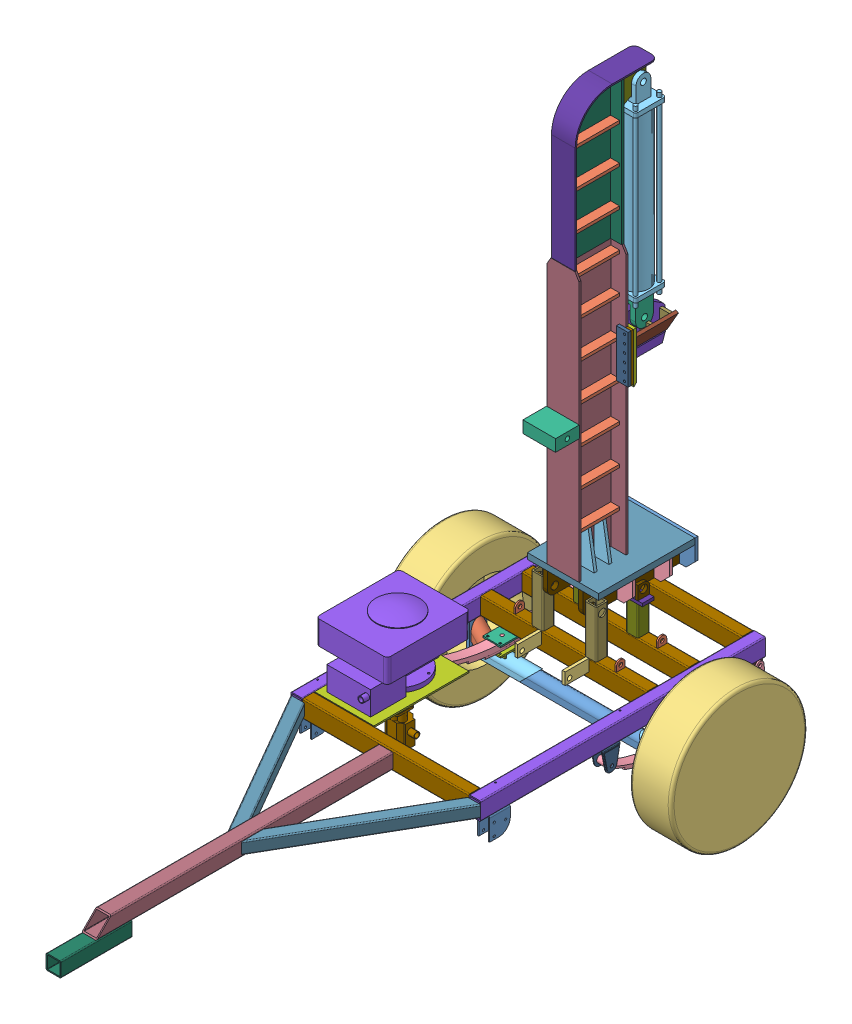
SolidWorks assembly Wood Splitter Mk4 Assb, configuration Upright. Lengths in mm.
Overall size (1041.53 2359.23 2641.6).
119 component instances, 51 part files, 48 mates.
Components (placement in the parent):
- Axle Assb-1: Axle Assb [Default] at (-785.5407 -217.0275 -452.1847) x (1 0 0) z (0 0.0044 0.99999) size (1270 586.82 669.93)
  - Axle-1: Axle [Default] at (861.7407 459.5998 794.3849) size (990.6 168.28 76.2)
  - Axle Brace-1: Axle Brace [Default] at (-125.416 485.8595 794.3849) x (0.707107 -0.707107 0) z (0 0 1) size (101.6 53.97 62.1)
  - Axle Brace-2: Axle Brace [Default] at (883.6975 485.8595 794.3849) x (-0.707107 -0.707107 0) z (0 0 -1) size (101.6 53.97 62.1)
  - Tire-1: Tire [Default] at (-166.9593 505.6373 794.3849) size (177.8 584.2 584.2)
  - Tire-2: Tire [Default] at (925.2407 505.6373 794.3849) x (-1 0 0) z (0 -0.004501 -0.99999) size (177.8 584.2 584.2)
  - 1750 Spring-1: 1750 Spring [Default] at (-1.8593 560.1132 794.3849) x (1 0 0) z (0 0 -1) size (44.45 133.46 669.92)
  - 1750 Spring-2: 1750 Spring [Default] at (760.1407 560.1132 794.3849) x (1 0 0) z (0 0 -1) size (44.45 133.46 669.92)
  - Axle Brace Horz-1: Axle Brace Horz [Default] at (158.8167 408.7998 794.3849) x (-1 0 0) z (0 0 -1) size (228.6 53.97 62.1)
  - Axle Brace Horz-2: Axle Brace Horz [Default] at (599.4648 408.7998 794.3849) size (228.6 53.97 62.1)
  - Spring Tie Plate-1: Spring Tie Plate [Default] at (-1.8593 487.2961 794.3849) size (76.2 6.35 88.9)
  - Spring Tie Plate-2: Spring Tie Plate [Default] at (760.1407 487.2961 794.3849) size (76.2 6.35 88.9)
  - Spring Seat-1: Spring Seat [Default] at (-1.8593 449.1961 794.3849) size (76.2 19.05 88.9)
  - Spring Seat-2: Spring Seat [Default] at (760.1407 449.1961 794.3849) size (76.2 19.05 88.9)
- Frame Assb-1: Frame Assb [Default] at (-1059.4886 145.9039 92.6772) size (819.15 374.65 2641.6)
  - Frame Tube Side-1: Frame Tube Side [Default] at (272.0886 310.0325 516.9228) size (50.8 76.2 1219.2)
  - Frame Tube End-1: Frame Tube End [Default] at (653.0886 310.0325 -67.2772) size (711.2 76.2 50.8)
  - Frame Tube Side-2: Frame Tube Side [Default] at (1034.0886 310.0325 516.9228) size (50.8 76.2 1219.2)
  - Spring Hanger Front-1: Spring Hanger Front [Default] at (272.0886 221.1325 567.7228) size (57.15 95.25 76.2)
  - Spring Hanger Front-2: Spring Hanger Front [Default] at (1034.0886 221.1325 567.7228) size (57.15 95.25 76.2)
  - Shackle Block-1: Shackle Block [Default] at (1034.0886 256.0575 -67.2772) size (44.45 31.75 31.75)
  - Shackle Block-2: Shackle Block [Default] at (272.0886 256.0575 -67.2772) size (44.45 31.75 31.75)
  - Frame Tube End-2: Frame Tube End [Default] at (653.0886 310.0325 1101.1228) size (711.2 76.2 50.8)
  - Frame Tube End-3: Frame Tube End [Default] at (653.0886 310.0325 339.1228) size (711.2 76.2 50.8)
  - Frame Tube End-4: Frame Tube End [Default] at (653.0886 310.0325 161.3228) size (711.2 76.2 50.8)
  - 5x8 Beam Pivot-1: 5x8 Beam Pivot [Default] at (538.7886 449.7325 339.1228) size (50.8 203.2 50.8)
  - 5x8 Beam Pivot-2: 5x8 Beam Pivot [Default] at (767.3886 449.7325 339.1228) size (50.8 203.2 50.8)
  - Frame Tounge-1: Frame Tounge [Default] at (653.0886 310.0325 1761.5228) size (63.5 63.5 1270)
  - Frame Tounge Side-1: Frame Tounge Side [Default] at (850.1665 310.0325 1438.2792) x (0.866025 0 0.5) z (-0.5 0 0.866025) size (50.8 50.8 749.3)
  - Frame Tounge Side-2: Frame Tounge Side [Default] at (456.0106 310.0325 1438.2792) x (-0.866025 0 0.5) z (0.5 0 0.866025) size (50.8 50.8 749.3)
  - Frame Tounge Extension-1: Frame Tounge Extension [Default] at (653.0886 246.5325 2396.5228) size (63.5 63.5 304.8)
  - 5x8 Beam Lock-1: 5x8 Beam Lock [Default] at (538.7886 411.6325 161.3228) size (50.8 127 50.8)
  - 5x8 Beam Lock-2: 5x8 Beam Lock [Default] at (767.3886 411.6325 161.3228) size (50.8 127 50.8)
  - 5x8 Beam Stop-1: 5x8 Beam Stop [Default] at (726.1136 481.4825 161.3228) size (171.45 12.7 50.8)
  - 5x8 Beam Lock Tab-1: 5x8 Beam Lock Tab [Default] at (519.7386 516.4075 161.3228) size (12.7 57.15 50.8)
  - 5x8 Beam Lock Tab-2: 5x8 Beam Lock Tab [Default] at (786.4386 516.4075 161.3228) size (12.7 57.15 50.8)
  - Castor Mount-1: Castor Mount [Default] at (1034.0886 221.1325 1043.9728) size (50.8 95.25 88.9)
  - Castor Mount-2: Castor Mount [Default] at (272.0886 221.1325 1043.9728) size (50.8 95.25 88.9)
  - Log Lift Clevis-1: Log Lift Clevis [Default] at (437.1886 367.1825 339.1228) size (6.35 38.1 38.1)
  - Log Lift Clevis-2: Log Lift Clevis [Default] at (437.1886 367.1825 161.3228) size (6.35 38.1 38.1)
  - Log Lift Clevis-3: Log Lift Clevis [Default] at (868.9886 367.1825 161.3228) size (6.35 38.1 38.1)
  - Log Lift Clevis-4: Log Lift Clevis [Default] at (868.9886 367.1825 339.1228) size (6.35 38.1 38.1)
  - Lift Clevis Lower-1: Lift Clevis Lower [Default] at (551.4886 322.7325 415.3228) size (12.7 50.8 101.6)
  - Lift Clevis Lower-2: Lift Clevis Lower [Default] at (754.6886 322.7325 415.3228) size (12.7 50.8 101.6)
- Shackle-1: Shackle [Default] at (0 373.5629 22.2281) x (1 0 0) z (0 -0.111002 0.99382)
- Shackle-2: Shackle [Default] at (-50.8 373.5629 22.2281) x (1 0 0) z (0 -0.111002 0.99382)
- Shackle-3: Shackle [Default] at (-762 373.5629 22.2281) x (1 0 0) z (0 -0.111002 0.99382)
- Shackle-4: Shackle [Default] at (-812.8 373.5629 22.2281) x (1 0 0) z (0 -0.111002 0.99382)
- Lion 40TH24-175-1: Lion 40TH24-175 [Retracted] at (-621.9267 1611.0795 -578.2318) size (130.18 939.8 130.18)
  - Lion 40TH24-175 Cylinder-1: Lion 40TH24-175 Cylinder [Default] at (218.7017 743.5068 730.6318) size (130.18 831.85 130.18)
  - Lion 40TH24-175 Rod-1: Lion 40TH24-175 Rod [Default] at (218.7017 721.2818 730.6318) size (101.6 822.32 101.6)
- Wedge Mk2 Assb-1: Wedge Mk2 Assb [Default] at (-365.761 1417.0554 373.2909) x (-1 0 0) z (0 0 -1) size (184.15 212.72 238.12)
  - Wedge Mk2 Base-1: Wedge Mk2 Base [Default] at (37.464 81.8685 125.6409) size (184.15 212.72 12.7)
  - Wedge Mk2-1: Wedge Mk2 [Default] at (37.464 -14.969 233.5909) size (25.4 203.2 203.2)
  - Wedge Mk2 Spacer-1: Wedge Mk2 Spacer [Default] at (-42.7048 86.631 114.5284) x (-1 0 0) z (0 0 1) size (23.81 203.2 9.53)
  - Wedge Mk2 Spacer-2: Wedge Mk2 Spacer [Default] at (117.6327 86.631 114.5284) size (23.81 203.2 9.53)
  - Wedge Mk2 Guide-1: Wedge Mk2 Guide [Default] at (104.139 86.631 103.4159) x (-1 0 0) z (0 0 1) size (50.8 203.2 12.7)
  - Wedge Mk2 Guide-2: Wedge Mk2 Guide [Default] at (-29.211 86.631 103.4159) size (50.8 203.2 12.7)
  - Wedge Mk2 Spreader-1: Wedge Mk2 Spreader [Default] at (75.564 89.1221 233.5909) x (0.866025 -0.5 0) z (0 0 1) size (12.7 101.6 203.2)
  - Wedge Mk2 Spreader-2: Wedge Mk2 Spreader [Default] at (-0.636 89.1221 233.5909) x (-0.866025 -0.5 0) z (0 0 -1) size (12.7 101.6 203.2)
  - Wedge Mk2 Spreader Support-1: Wedge Mk2 Spreader Support [Default] at (24.764 134.028 151.0409) x (-1 0 0) z (0 0 -1) size (43.99 76.2 12.7)
  - Wedge Mk2 Spreader Support-2: Wedge Mk2 Spreader Support [Default] at (24.764 134.028 233.5909) x (-1 0 0) z (0 0 -1) size (43.99 76.2 12.7)
  - Wedge Mk2 Spreader Support-3: Wedge Mk2 Spreader Support [Default] at (24.764 134.028 316.1409) x (-1 0 0) z (0 0 -1) size (43.99 76.2 12.7)
  - Wedge Mk2 Spreader Support-4: Wedge Mk2 Spreader Support [Default] at (50.164 134.028 316.1409) size (43.99 76.2 12.7)
  - Wedge Mk2 Spreader Support-5: Wedge Mk2 Spreader Support [Default] at (50.164 134.028 233.5909) size (43.99 76.2 12.7)
  - Wedge Mk2 Spreader Support-6: Wedge Mk2 Spreader Support [Default] at (50.164 134.028 151.0409) size (43.99 76.2 12.7)
- 5x8 Rail Assb-1: 5x8 Rail Assb [Default] at (-973.7037 763.2009 -461.3249) size (304.8 1885.95 527.05)
  - 5x8 Beam-1: 5x8 Beam [Default] at (570.4787 569.0354 820.0999) size (136.53 1143 209.55)
  - 5x8 Reaction Plate-1: 5x8 Reaction Plate [Default] at (570.4787 -15.1646 718.4999) size (304.8 25.4 412.75)
  - 4x8 Beam-1: 4x8 Beam [Default] at (570.4787 1445.3354 715.3249) size (101.6 609.6 201.61)
  - Clevis Mount-1: Clevis Mount [Default] at (570.4787 1696.1604 648.6499) size (25.4 152.4 133.35)
  - 4x8 Beam Bottom-1: 4x8 Beam Bottom [Default] at (570.4787 1597.7354 764.5374) size (101.6 615.95 354.01)
  - 5x8 Beam Pivot Plate-1: 5x8 Beam Pivot Plate [Default] at (494.2787 -78.6646 718.4999) size (19.05 101.6 412.75)
  - 5x8 Beam Pivot Plate-2: 5x8 Beam Pivot Plate [Default] at (646.6787 -78.6646 718.4999) size (19.05 101.6 412.75)
  - Reaction Plate Front Brace-1: Reaction Plate Front Brace [Default] at (570.4787 -65.9646 505.7749) size (304.8 127 12.7)
  - 5x8 Beam Gusset-1: 5x8 Beam Gusset [Default] at (592.7037 473.7854 820.0999) x (0 0 -1) z (1 0 0) size (193.68 12.7 38.1)
  - 5x8 Beam Gusset-2: 5x8 Beam Gusset [Default] at (592.7037 315.0354 820.0999) x (0 0 -1) z (1 0 0) size (193.68 12.7 38.1)
  - 5x8 Beam Gusset-3: 5x8 Beam Gusset [Default] at (592.7037 632.5354 820.0999) x (0 0 -1) z (1 0 0) size (193.68 12.7 38.1)
  - 5x8 Beam Gusset-4: 5x8 Beam Gusset [Default] at (592.7037 950.0354 820.0999) x (0 0 -1) z (1 0 0) size (193.68 12.7 38.1)
  - 5x8 Beam Gusset-5: 5x8 Beam Gusset [Default] at (592.7037 791.2854 820.0999) x (0 0 -1) z (1 0 0) size (193.68 12.7 38.1)
  - 5x8 Beam Gusset-6: 5x8 Beam Gusset [Default] at (592.7037 1108.7854 820.0999) x (0 0 -1) z (1 0 0) size (193.68 12.7 38.1)
  - 5x8 Beam Gusset-7: 5x8 Beam Gusset [Default] at (592.7037 156.2854 820.0999) x (0 0 -1) z (1 0 0) size (193.68 12.7 38.1)
  - 5x8 Beam Gusset-8: 5x8 Beam Gusset [Default] at (548.2537 1108.7854 820.0999) x (0 0 1) z (-1 0 0) size (193.68 12.7 38.1)
  - 5x8 Beam Gusset-9: 5x8 Beam Gusset [Default] at (548.2537 950.0354 820.0999) x (0 0 1) z (-1 0 0) size (193.68 12.7 38.1)
  - 5x8 Beam Gusset-10: 5x8 Beam Gusset [Default] at (548.2537 791.2854 820.0999) x (0 0 1) z (-1 0 0) size (193.68 12.7 38.1)
  - 5x8 Beam Gusset-11: 5x8 Beam Gusset [Default] at (548.2537 632.5354 820.0999) x (0 0 1) z (-1 0 0) size (193.68 12.7 38.1)
  - 5x8 Beam Gusset-12: 5x8 Beam Gusset [Default] at (548.2537 473.7854 820.0999) x (0 0 1) z (-1 0 0) size (193.68 12.7 38.1)
  - 5x8 Beam Gusset-13: 5x8 Beam Gusset [Default] at (548.2537 315.0354 820.0999) x (0 0 1) z (-1 0 0) size (193.68 12.7 38.1)
  - 5x8 Beam Gusset-14: 5x8 Beam Gusset [Default] at (548.2537 156.2854 820.0999) x (0 0 1) z (-1 0 0) size (193.68 12.7 38.1)
  - Reaction Plate Center Gusset-1: Reaction Plate Center Gusset [Default] at (570.4787 -78.6646 772.4749) size (133.35 101.6 12.7)
  - Reaction Plate Center Gusset-2: Reaction Plate Center Gusset [Default] at (570.4787 -78.6646 613.7249) size (133.35 101.6 12.7)
  - Reaction Plate Edge Gusset-1: Reaction Plate Edge Gusset [Default] at (451.4162 -78.6646 772.4749) x (-1 0 0) z (0 0 -1) size (66.67 101.6 12.7)
  - Reaction Plate Edge Gusset-2: Reaction Plate Edge Gusset [Default] at (451.4162 -78.6646 613.7249) x (-1 0 0) z (0 0 -1) size (66.67 101.6 12.7)
  - Reaction Plate Edge Gusset-3: Reaction Plate Edge Gusset [Default] at (689.5412 -78.6646 613.7249) size (66.67 101.6 12.7)
  - Reaction Plate Edge Gusset-4: Reaction Plate Edge Gusset [Default] at (689.5412 -78.6646 772.4749) size (66.67 101.6 12.7)
  - Reaction Plate Front Gusset-1: Reaction Plate Front Gusset [Default] at (605.4037 73.7354 851.8499) x (-1 0 0) z (0 0 -1) size (63.5 152.4 12.7)
  - Reaction Plate Front Gusset-2: Reaction Plate Front Gusset [Default] at (605.4037 73.7354 788.3499) x (-1 0 0) z (0 0 -1) size (63.5 152.4 12.7)
  - Reaction Plate Front Gusset-3: Reaction Plate Front Gusset [Default] at (535.5537 73.7354 788.3499) size (63.5 152.4 12.7)
  - Reaction Plate Front Gusset-4: Reaction Plate Front Gusset [Default] at (535.5537 73.7354 851.8499) size (63.5 152.4 12.7)
  - 5x8 Beam Gusset-15: 5x8 Beam Gusset [Default] at (593.4975 1273.8854 820.8937) x (0 0 -1) z (1 0 0) size (193.68 12.7 38.1)
  - 5x8 Beam Gusset-16: 5x8 Beam Gusset [Default] at (593.4975 1432.6354 820.8937) x (0 0 -1) z (1 0 0) size (193.68 12.7 38.1)
  - 5x8 Beam Gusset-17: 5x8 Beam Gusset [Default] at (593.4975 1591.3854 820.8937) x (0 0 -1) z (1 0 0) size (193.68 12.7 38.1)
  - 5x8 Beam Gusset-18: 5x8 Beam Gusset [Default] at (547.46 1273.8854 820.8937) x (0 0 1) z (-1 0 0) size (193.68 12.7 38.1)
  - 5x8 Beam Gusset-19: 5x8 Beam Gusset [Default] at (547.46 1432.6354 820.8937) x (0 0 1) z (-1 0 0) size (193.68 12.7 38.1)
  - 5x8 Beam Gusset-20: 5x8 Beam Gusset [Default] at (547.46 1591.3854 820.8937) x (0 0 1) z (-1 0 0) size (193.68 12.7 38.1)
  - Jack Clevis Beam-1: Jack Clevis Beam [Default] at (570.4787 556.3354 975.6749) size (139.7 50.8 101.6)
- Floor-1: Floor [Default] at (-409.2151 -12.7 1208.2581) (hidden)
- table mockup right side-1: table mockup right side [Default] at (-288.925 762.3238 279.4) (hidden)
- table mockup left side-1: table mockup left side [Default] at (-523.875 762.3238 279.4) (hidden)
- Engine Pump Assb-1: Engine Pump Assb [Default] at (-957.0821 332.8088 1040.264) x (0 0 -1) z (1 0 0) size (431.8 509.78 304.8)
  - Engine Mount Plate-1: Engine Mount Plate [Default] at (75.064 158.0526 322.0821) size (406.4 6.35 254)
  - Intek 190cc-1: Intek 190cc [Default] at (125.864 180.2776 296.6821) size (431.8 325.75 304.8)
  - Concentric 1300486 Pump-1: Concentric 1300486 Pump [Default] at (135.3877 -105.3454 296.8411) x (-0.016696 0 0.999861) z (-0.999861 0 -0.016696) size (119 177.67 80.16)
- Hydraulic Tank Assb-1: Hydraulic Tank Assb [Default] at (-421.6329 127.7556 393.9151) size (355.6 279.4 609.6) (hidden)
  - Hydraulic Tank-1: Hydraulic Tank [Default] at (218.4329 144.0307 456.9849) size (279.4 279.4 609.6)
  - Hydraulic Tank Mount Angle Right-1: Hydraulic Tank Mount Angle Right [Default] at (358.1329 366.2807 723.6849) size (38.1 38.1 76.2)
  - Hydraulic Tank Mount Angle Right-2: Hydraulic Tank Mount Angle Right [Default] at (358.1329 366.2807 190.2849) size (38.1 38.1 76.2)
  - Hydraulic Tank Mount Angle Left-1: Hydraulic Tank Mount Angle Left [Default] at (78.7329 366.2807 190.2849) size (38.1 38.1 76.2)
  - Hydraulic Tank Mount Angle Left-2: Hydraulic Tank Mount Angle Left [Default] at (78.7329 366.2807 723.6849) size (38.1 38.1 76.2)
Mates (geometry in assembly coordinates):
- Coincident1: coincident anti-aligned: plane of Axle Assb-1/1750 Spring-1 through (-765.175 345.1645 19.0562) normal (1 0 0); plane of Frame Assb-1/Spring Hanger Front-1 through (-765.175 413.0738 698.5) normal (-1 0 0)
- Concentric2: concentric anti-aligned: cylinder of Frame Assb-1/Shackle Block-1 through (-3.175 401.9613 25.4) axis (-1 0 0) radius 8.89; cylinder of Shackle-1 through (-3.176 401.9613 25.4) axis (1 0 0) radius 7.1437
- Concentric3: concentric anti-aligned: cylinder of Axle Assb-1/1750 Spring-2 through (-3.175 345.1645 19.0562) axis (-1 0 0) radius 6.35; cylinder of Shackle-1 through (-3.176 345.1645 19.0562) axis (1 0 0) radius 7.1437
- Concentric4: concentric anti-aligned: cylinder of Frame Assb-1/Shackle Block-1 through (-3.175 401.9613 25.4) axis (-1 0 0) radius 8.89; cylinder of Shackle-2 through (-53.976 401.9613 25.4) axis (1 0 0) radius 7.1437
- Concentric5: concentric anti-aligned: cylinder of Axle Assb-1/1750 Spring-2 through (-3.175 345.1645 19.0562) axis (-1 0 0) radius 6.35; cylinder of Shackle-2 through (-53.976 345.1645 19.0562) axis (1 0 0) radius 7.1437
- Coincident2: coincident anti-aligned: plane of Frame Assb-1/Shackle Block-1 through (-3.175 401.9613 25.4) normal (1 0 0); plane of Shackle-1 through (-3.175 345.1645 19.0562) normal (-1 0 0)
- Coincident3: coincident anti-aligned: plane of Frame Assb-1/Shackle Block-1 through (-47.625 401.9613 25.4) normal (-1 0 0); plane of Shackle-2 through (-47.625 345.1645 19.0562) normal (1 0 0)
- Concentric6: concentric anti-aligned: cylinder of Frame Assb-1/Shackle Block-2 through (-765.175 401.9613 25.4) axis (-1 0 0) radius 8.89; cylinder of Shackle-3 through (-765.176 401.9613 25.4) axis (1 0 0) radius 7.1437
- Concentric7: concentric anti-aligned: cylinder of Axle Assb-1/1750 Spring-1 through (-765.175 345.1645 19.0562) axis (-1 0 0) radius 6.35; cylinder of Shackle-3 through (-765.176 345.1645 19.0562) axis (1 0 0) radius 7.1437
- Concentric8: concentric anti-aligned: cylinder of Axle Assb-1/1750 Spring-1 through (-765.175 345.1645 19.0562) axis (-1 0 0) radius 6.35; cylinder of Shackle-4 through (-815.976 345.1645 19.0562) axis (1 0 0) radius 7.1437
- Concentric9: concentric anti-aligned: cylinder of Frame Assb-1/Shackle Block-2 through (-765.175 401.9613 25.4) axis (-1 0 0) radius 8.89; cylinder of Shackle-4 through (-815.976 401.9613 25.4) axis (1 0 0) radius 7.1437
- Coincident4: coincident anti-aligned: plane of Frame Assb-1/Shackle Block-2 through (-809.625 401.9613 25.4) normal (-1 0 0); plane of Shackle-4 through (-809.625 345.1645 19.0562) normal (1 0 0)
- Coincident5: coincident anti-aligned: plane of Frame Assb-1/Shackle Block-2 through (-765.175 401.9613 25.4) normal (1 0 0); plane of Shackle-3 through (-765.175 345.1645 19.0562) normal (-1 0 0)
- Concentric10: concentric aligned: cylinder of Lion 40TH24-175-1/Lion 40TH24-175 Rod-1 through (-446.0875 989.2146 116.0033) axis (1 0 0) radius 14.2875; cylinder of ? through (-419.1 989.2146 116.0033) axis (1 0 0) radius 14.2875
- Coincident6: coincident anti-aligned: plane of Lion 40TH24-175-1/Lion 40TH24-175 Rod-1 through (-393.7 951.1146 65.2023) normal (-1 0 0); plane of ? through (-393.7 989.2146 116.0033) normal (1 0 0)
- Tangent1: tangent anti-aligned: cylinder of Axle Assb-1/Tire-1 through (-1041.4 292.1 339.9678) axis (-1 0 0) radius 292.1; plane of assembly through (0 0 0) normal (0 1 0)
- Tangent2: tangent anti-aligned: cylinder of Axle Assb-1/Tire-2 through (228.6 292.1 339.9678) axis (1 0 0) radius 292.1; plane of assembly through (0 0 0) normal (0 1 0)
- Concentric11: concentric aligned: cylinder of Frame Assb-1/5x8 Beam Pivot-2 through (-317.5 665.4863 431.8) axis (1 0 0) radius 16.002; cylinder of 5x8 Rail Assb-1/5x8 Beam Pivot Plate-2 through (-336.551 665.4863 431.8) axis (1 0 0) radius 15.875
- Parallel2: parallel aligned: plane of Frame Assb-1/Frame Tube Side-2 through (-46.0375 494.0363 1219.2) normal (0 1 0); plane of assembly through (0 0 0) normal (0 1 0)
- Parallel3: parallel anti-aligned: plane of Frame Assb-1/Frame Tube End-1 through (-50.8 489.2738 0) normal (0 0 -1); plane of assembly through (0 0 0) normal (0 0 1)
- Coincident11: coincident aligned: plane of Frame Assb-1/Frame Tube Side-2 through (0 489.2738 1219.2) normal (1 0 0); plane of assembly through (0 0 0) normal (1 0 0)
- Coincident12: coincident anti-aligned: plane of 5x8 Rail Assb-1/5x8 Beam Pivot Plate-2 through (-317.5 684.5363 257.175) normal (1 0 0); plane of Frame Assb-1/5x8 Beam Pivot-2 through (-317.5 697.2363 450.85) normal (-1 0 0)
- Coincident13: coincident anti-aligned: plane of Frame Assb-1/Frame Tube End-1 through (-50.8 489.2738 0) normal (0 0 -1); plane of assembly through (0 0 0) normal (0 0 1)
- Parallel4: parallel anti-aligned: plane of Frame Assb-1/Frame Tube Side-2 through (-46.0375 462.9845 1219.2) normal (0 1 0); plane of 5x8 Rail Assb-1/5x8 Beam-1
- Parallel5: parallel aligned: plane of Frame Assb-1/5x8 Beam Pivot-2 through (-311.15 697.2363 457.2) normal (0 0 1); plane of 5x8 Rail Assb-1/5x8 Beam-1 through (-334.9625 1903.7363 463.55) normal (0 0 1)
- Coincident14: coincident anti-aligned: plane of Wedge Mk2 Assb-1/Wedge Mk2 Base-1 through (-403.225 1498.9238 254) normal (0 0 1); plane of 5x8 Rail Assb-1/5x8 Beam-1 through (-471.4875 1903.7363 254) normal (0 0 -1)
- Coincident16: coincident aligned: line of Wedge Mk2 Assb-1/Wedge Mk2 Base-1 through (-403.225 1605.2863 254) axis (0 -1 0); line of 5x8 Rail Assb-1/5x8 Beam-1 through (-403.225 1903.7363 254) axis (0 -1 0)
- Parallel6: parallel anti-aligned: plane of Lion 40TH24-175-1/Lion 40TH24-175 Cylinder-1 through (-347.6625 1668.7863 217.4875) normal (0 0 1); plane of 5x8 Rail Assb-1/5x8 Beam-1 through (-471.4875 1903.7363 254) normal (0 0 -1)
- Parallel7: parallel aligned: plane of Frame Assb-1/Frame Tube Side-2 through (-46.0375 494.0363 1219.2) normal (0 1 0); plane of Floor-1 through (-409.2151 0 1208.2581) normal (0 1 0)
- Tangent3: tangent anti-aligned: cylinder of Axle Assb-1/Tire-1 through (-1041.4 292.1 339.9678) axis (-1 0 0) radius 292.1; plane of Floor-1 through (-409.2151 0 1208.2581) normal (0 1 0)
- Concentric12: concentric anti-aligned: cylinder of ? through (-263.525 646.4363 254) axis (0 -1 0) radius 20.6375; cylinder of table mockup right side-1 through (-263.525 557.5363 254) axis (0 1 0) radius 17.4625
- Coincident18: coincident anti-aligned: plane of ? through (-263.525 646.4363 254) normal (0 1 0); plane of table mockup right side-1 through (-263.525 646.4363 254) normal (0 -1 0)
- Concentric13: concentric anti-aligned: cylinder of ? through (-549.275 646.4363 254) axis (0 -1 0) radius 17.4625; cylinder of table mockup left side-1 through (-549.275 557.5363 254) axis (0 1 0) radius 17.4625
- Coincident19: coincident anti-aligned: plane of ? through (-549.275 646.4363 254) normal (0 1 0); plane of table mockup left side-1 through (-549.275 646.4363 254) normal (0 -1 0)
- Parallel10: parallel anti-aligned: plane of 5x8 Rail Assb-1/5x8 Reaction Plate-1 through (-250.825 760.7363 50.8) normal (1 0 0); plane of table mockup right side-1 through (-288.925 763.9113 279.4) normal (-1 0 0)
- Parallel9: parallel anti-aligned: plane of 5x8 Rail Assb-1/5x8 Reaction Plate-1 through (-555.625 760.7363 50.8) normal (-1 0 0); plane of table mockup left side-1 through (-523.875 763.9113 279.4) normal (1 0 0)
- Parallel11: parallel anti-aligned: plane of 5x8 Rail Assb-1/5x8 Beam-1 through (-403.225 843.9845 1651) normal (1 0 0); plane of table mockup right side-1
- Parallel12: parallel anti-aligned: plane of 5x8 Rail Assb-1/5x8 Beam-1 through (-409.575 650.3095 1651) normal (-1 0 0); plane of table mockup left side-1
- Concentric14: concentric anti-aligned: cylinder of Lion 40TH24-175-1/Lion 40TH24-175 Cylinder-1 through (-369.8875 2443.4863 152.4) axis (-1 0 0) radius 12.7; cylinder of 5x8 Rail Assb-1/Clevis Mount-1 through (-415.926 2443.4863 152.4) axis (1 0 0) radius 12.7
- Concentric15: concentric anti-aligned: cylinder of Axle Assb-1/1750 Spring-1 through (-765.175 347.9863 660.4) axis (-1 0 0) radius 6.35; cylinder of Frame Assb-1/Spring Hanger Front-1 through (-815.975 347.9863 660.4) axis (1 0 0) radius 7.1437
- Coincident20: coincident anti-aligned: plane of Frame Assb-1/Frame Tube Side-1 through (-762 489.2738 1219.2) normal (1 0 0); plane of Engine Pump Assb-1/Engine Mount Plate-1 through (-762 494.0363 1168.4) normal (-1 0 0)
- Coincident21: coincident anti-aligned: plane of Frame Assb-1/Frame Tube End-2 through (-50.8 489.2738 1168.4) normal (0 0 -1); plane of Engine Pump Assb-1/Engine Mount Plate-1 through (-762 494.0363 1168.4) normal (0 0 1)
- Coincident22: coincident aligned: plane of Frame Assb-1/Frame Tube End-2 through (-50.8 494.0363 1214.4375) normal (0 1 0); plane of Engine Pump Assb-1/Engine Mount Plate-1 through (-635 494.0363 965.2) normal (0 1 0)
- Concentric16: concentric aligned: cylinder of Frame Assb-1/Frame Tube Side-2 through (-38.1 494.0363 1117.6) axis (0 1 0) radius 3.2639; cylinder of Hydraulic Tank Assb-1/Hydraulic Tank Mount Angle Right-1 through (-38.1 494.0353 1117.6) axis (0 1 0) radius 4.3656
- Concentric17: concentric aligned: cylinder of Frame Assb-1/Frame Tube Side-2 through (-38.1 494.0363 584.2) axis (0 1 0) radius 3.2639; cylinder of Hydraulic Tank Assb-1/Hydraulic Tank Mount Angle Right-2 through (-38.1 494.0353 584.2) axis (0 1 0) radius 4.3656
- Coincident23: coincident anti-aligned: plane of Frame Assb-1/Frame Tube Side-2 through (-46.0375 494.0363 1219.2) normal (0 1 0); plane of Hydraulic Tank Assb-1/Hydraulic Tank Mount Angle Right-1 through (-63.5 494.0363 1155.7) normal (0 -1 0)
- Concentric18: concentric anti-aligned: cylinder of Lion 40TH24-175-1/Lion 40TH24-175 Rod-1 through (-441.325 1573.5363 152.4) axis (1 0 0) radius 12.7; cylinder of Wedge Mk2 Assb-1/Wedge Mk2-1 through (-390.524 1573.5363 152.4) axis (-1 0 0) radius 12.7
- Coincident24: coincident: point of Lion 40TH24-175-1/Lion 40TH24-175 Cylinder-1; point of 5x8 Rail Assb-1/Clevis Mount-1
